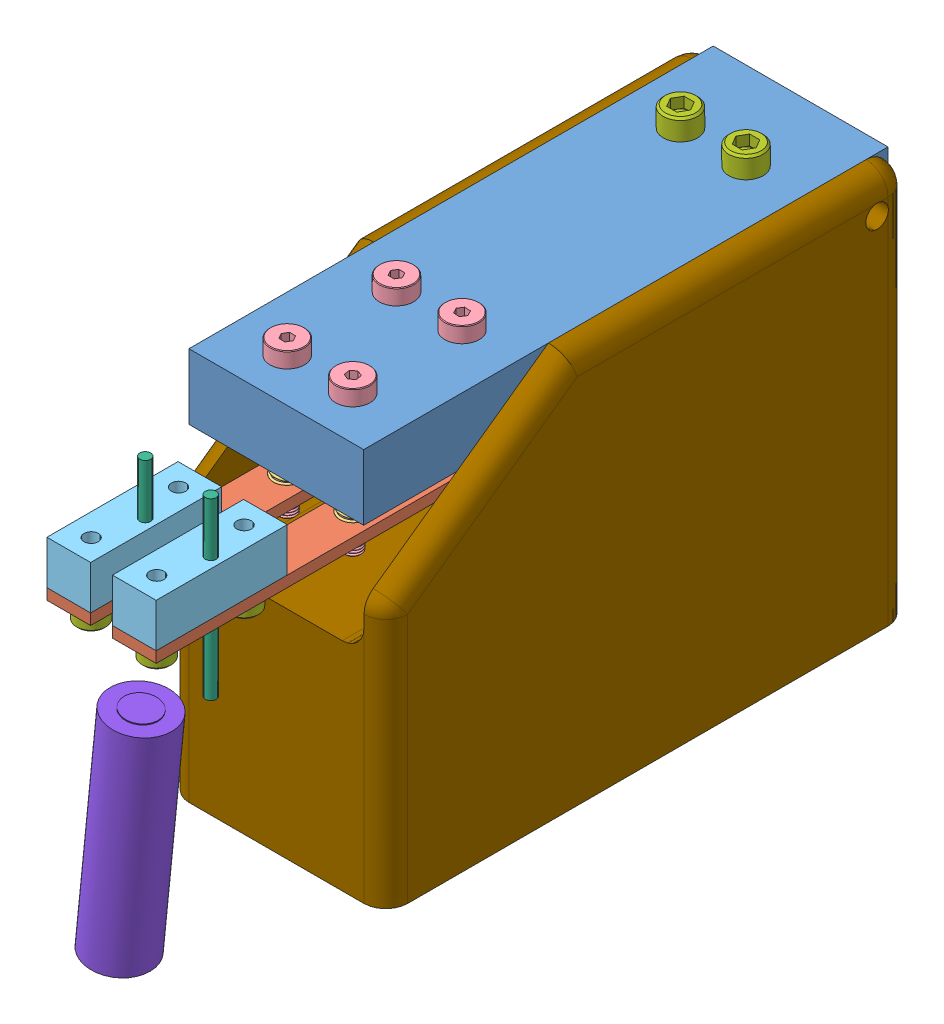
SolidWorks assembly WelderArmAssy, configuration Default. Lengths in mm.
Overall size (63.5 125.04 207.43).
23 component instances, 9 part files, 40 mates.
Components (placement in the parent):
- WelderArm-1: WelderArm [Default] at origin size (50.8 19.05 152.4)
- copperBusBar-1: copperBusBar [Default] at (28.575 -14.125 0) size (12.7 3.17 203.2)
- copperBusBar-2: copperBusBar [Default] at (9.525 -14.125 0) size (12.7 3.17 203.2)
- 9657K303_STEEL COMPRESSION SPRING-1: 9657K303_STEEL COMPRESSION SPRING [9657K303] at (34.8782 -10.95 139.5847) x (1 0 0) z (0 -1 0) size (8.16 8.28 25.73)
- socket head shoulder screw2_am-1: socket head shoulder screw2_am [B18.3.3M - 6.5 x 30 SHSS --S] at (34.925 23.55 139.7) x (0 -1 0) z (0.988219 0 -0.153046) size (44.25 10 10)
- socket head shoulder screw2_am-2: socket head shoulder screw2_am [B18.3.3M - 6.5 x 30 SHSS --S] at (15.875 23.55 139.7) x (0 -1 0) z (-0.008465 0 0.999964) size (44.25 10 10)
- 9657K303_STEEL COMPRESSION SPRING-2: 9657K303_STEEL COMPRESSION SPRING [9657K303] at (15.8175 -10.95 139.7949) x (1 0 0) z (0 -1 0) size (8.16 8.28 25.73)
- socket head shoulder screw2_am-3: socket head shoulder screw2_am [B18.3.3M - 6.5 x 30 SHSS --S] at (15.875 23.55 107.95) x (0 -1 0) z (-0.008465 0 0.999964) size (44.25 10 10)
- socket head shoulder screw2_am-5: socket head shoulder screw2_am [B18.3.3M - 6.5 x 30 SHSS --S] at (34.925 23.55 107.95) x (0 -1 0) z (0.839971 0 0.542632) size (44.25 10 10)
- Mini_Bus_Block-3: Mini_Bus_Block [Default] at (41.275 -10.95 203.2) x (-1 0 0) z (0 0 -1) size (12.7 12.7 38.1)
- Mini_Bus_Block-4: Mini_Bus_Block [Default] at (22.225 -10.95 203.2) x (-1 0 0) z (0 0 -1) size (12.7 12.7 38.1)
- CopperElectrode-1: CopperElectrode [Default] at (38.1 -33.4948 184.15) x (0.72725 0 -0.686373) z (0.686373 0 0.72725) size (3.17 50.8 3.17)
- CopperElectrode-2: CopperElectrode [Default] at (19.05 -33.3788 184.15) x (-0.864045 0 0.503415) z (-0.503415 0 -0.864045) size (3.17 50.8 3.17)
- socket head cap screw_am-1: socket head cap screw_am [B18.3.1M - 5 x 0.8 x 10 Hex SHCS -- 10NHX] at (16.0317 -19.125 196.85) x (0 1 0) z (0 0 1) size (15 8.5 8.5)
- socket head cap screw_am-2: socket head cap screw_am [B18.3.1M - 5 x 0.8 x 10 Hex SHCS -- 10NHX] at (16.0317 -19.125 171.45) x (0 1 0) z (0.419205 0 0.907892) size (15 8.5 8.5)
- socket head cap screw_am-3: socket head cap screw_am [B18.3.1M - 5 x 0.8 x 10 Hex SHCS -- 10NHX] at (35.0817 -19.125 196.85) x (0 1 0) z (0 0 1) size (15 8.5 8.5)
- socket head cap screw_am-4: socket head cap screw_am [B18.3.1M - 5 x 0.8 x 10 Hex SHCS -- 10NHX] at (35.0817 -19.125 171.45) x (0 1 0) z (0 0 1) size (15 8.5 8.5)
- socket head cap screw_am-5: socket head cap screw_am [B18.3.1M - 6 x 1.0 x 40 Hex SHCS -- 24NHX] at (15.875 25.05 25.4) x (0 -1 0) z (0 0 1) size (46 10 10)
- socket head cap screw_am-7: socket head cap screw_am [B18.3.1M - 6 x 1.0 x 40 Hex SHCS -- 24NHX] at (34.925 25.05 25.4) x (0 -1 0) z (0 0 1) size (46 10 10)
- 9657K303_STEEL COMPRESSION SPRING-7: 9657K303_STEEL COMPRESSION SPRING [9657K303] at (34.5426 -10.95 108.0658) x (1 0 0) z (0 -1 0) size (8.16 8.28 25.73)
- 9657K303_STEEL COMPRESSION SPRING-8: 9657K303_STEEL COMPRESSION SPRING [9657K303] at (16.1134 -10.95 107.8329) x (1 0 0) z (0 -1 0) size (8.16 8.28 25.73)
- 18650-1: 18650 [Default] at (23.2712 -98.7389 195.9651) x (0.198702 -0.032867 0.979509) z (-0.973928 0.105003 0.201093) size (18.2 65 18.2)
- stand-1: stand [Default] at (57.15 -95.25 0) x (-1 0 0) z (0 0 -1) size (63.5 114.3 152.32)
Mates (geometry in assembly coordinates):
- Coincident1: coincident aligned: plane of WelderArm-1 through (0 0 0) normal (0 0 -1); plane of copperBusBar-2 through (9.525 -14.125 0) normal (0 0 -1)
- Coincident2: coincident aligned: plane of WelderArm-1 through (0 0 0) normal (0 0 -1); plane of copperBusBar-1 through (28.575 -14.125 0) normal (0 0 -1)
- Coincident4: coincident aligned: plane of copperBusBar-1 through (28.575 -10.95 203.2) normal (0 1 0); plane of copperBusBar-2 through (9.525 -10.95 203.2) normal (0 1 0)
- Distance3: distance = 9.525 mm aligned: plane of copperBusBar-1 through (41.275 -14.125 203.2) normal (1 0 0); plane of WelderArm-1 through (50.8 0 152.4) normal (1 0 0)
- Concentric1: concentric anti-aligned: cylinder of copperBusBar-1 through (34.925 -14.125 139.7) axis (0 -1 0) radius 2.1; cylinder of socket head shoulder screw2_am-1 through (34.925 29.9 139.7) axis (0 1 0) radius 3.2435
- Coincident7: coincident anti-aligned: plane of copperBusBar-1 through (28.575 -10.95 203.2) normal (0 1 0); plane of socket head shoulder screw2_am-1 through (34.4286 -10.95 136.4947) normal (0 -1 0)
- Coincident8: coincident anti-aligned: plane of copperBusBar-1 through (28.575 -10.95 203.2) normal (0 1 0); plane of 9657K303_STEEL COMPRESSION SPRING-1 through (34.8782 -10.95 139.5847) normal (0 -1 0)
- Concentric3: concentric anti-aligned: cylinder of copperBusBar-2 through (15.875 -14.125 139.7) axis (0 -1 0) radius 2.1; cylinder of socket head shoulder screw2_am-2 through (15.875 29.9 139.7) axis (0 1 0) radius 3.2435
- Coincident9: coincident anti-aligned: plane of copperBusBar-2 through (9.525 -10.95 203.2) normal (0 1 0); plane of socket head shoulder screw2_am-2 through (19.1184 -10.95 139.7275) normal (0 -1 0)
- Coincident10: coincident anti-aligned: plane of copperBusBar-2 through (9.525 -10.95 203.2) normal (0 1 0); plane of 9657K303_STEEL COMPRESSION SPRING-2 through (15.8175 -10.95 139.7949) normal (0 -1 0)
- Concentric4: concentric anti-aligned: cylinder of copperBusBar-2 through (15.875 -14.125 107.95) axis (0 -1 0) radius 2.1; cylinder of socket head shoulder screw2_am-3 through (15.875 29.9 107.95) axis (0 1 0) radius 3.2435
- Coincident11: coincident anti-aligned: plane of copperBusBar-2 through (9.525 -10.95 203.2) normal (0 1 0); plane of socket head shoulder screw2_am-3 through (19.1184 -10.95 107.9775) normal (0 -1 0)
- Concentric6: concentric anti-aligned: cylinder of copperBusBar-1 through (34.925 -14.125 107.95) axis (0 -1 0) radius 2.1; cylinder of socket head shoulder screw2_am-5 through (34.925 29.9 107.95) axis (0 1 0) radius 3.2435
- Coincident12: coincident anti-aligned: plane of copperBusBar-1 through (28.575 -10.95 203.2) normal (0 1 0); plane of socket head shoulder screw2_am-5 through (36.685 -10.95 105.2256) normal (0 -1 0)
- Coincident19: coincident aligned: plane of copperBusBar-1 through (28.575 -14.125 203.2) normal (0 0 1); plane of Mini_Bus_Block-3 through (41.275 -10.95 203.2) normal (0 0 1)
- Coincident20: coincident anti-aligned: plane of copperBusBar-1 through (28.575 -10.95 203.2) normal (0 1 0); plane of Mini_Bus_Block-3 through (41.275 -10.95 165.1) normal (0 -1 0)
- Coincident23: coincident aligned: plane of copperBusBar-2 through (9.525 -14.125 203.2) normal (0 0 1); plane of Mini_Bus_Block-4 through (22.225 -10.95 203.2) normal (0 0 1)
- Coincident24: coincident anti-aligned: plane of copperBusBar-2 through (9.525 -10.95 203.2) normal (0 1 0); plane of Mini_Bus_Block-4 through (22.225 -10.95 165.1) normal (0 -1 0)
- Coincident25: coincident aligned: plane of copperBusBar-2 through (22.225 -14.125 203.2) normal (1 0 0); plane of Mini_Bus_Block-4 through (22.225 -10.95 165.1) normal (1 0 0)
- Concentric7: concentric anti-aligned: cylinder of Mini_Bus_Block-3 through (38.1 1.75 184.15) axis (0 1 0) radius 1.5875; cylinder of CopperElectrode-1 through (38.1 17.3052 184.15) axis (0 -1 0) radius 1.5875
- Concentric8: concentric anti-aligned: cylinder of Mini_Bus_Block-4 through (19.05 1.75 184.15) axis (0 1 0) radius 1.5875; cylinder of CopperElectrode-2 through (19.05 17.4212 184.15) axis (0 -1 0) radius 1.5875
- Concentric9: concentric anti-aligned: cylinder of Mini_Bus_Block-4 through (16.0317 1.75 171.45) axis (0 1 0) radius 2.1; cylinder of socket head cap screw_am-2 through (16.0317 -50.875 171.45) axis (0 -1 0) radius 2.5
- Coincident26: coincident anti-aligned: plane of copperBusBar-2 through (9.525 -14.125 203.2) normal (0 -1 0); plane of socket head cap screw_am-2 through (12.1732 -14.125 173.2316) normal (0 1 0)
- Concentric10: concentric anti-aligned: cylinder of Mini_Bus_Block-4 through (16.0317 1.75 196.85) axis (0 1 0) radius 2.1; cylinder of socket head cap screw_am-1 through (16.0317 -50.875 196.85) axis (0 -1 0) radius 2.5
- Coincident27: coincident anti-aligned: plane of copperBusBar-2 through (9.525 -14.125 203.2) normal (0 -1 0); plane of socket head cap screw_am-1 through (11.7817 -14.125 196.85) normal (0 1 0)
- Concentric11: concentric anti-aligned: cylinder of Mini_Bus_Block-3 through (35.0817 1.75 196.85) axis (0 1 0) radius 2.1; cylinder of socket head cap screw_am-3 through (35.0817 -50.875 196.85) axis (0 -1 0) radius 2.5
- Coincident28: coincident anti-aligned: plane of copperBusBar-1 through (28.575 -14.125 203.2) normal (0 -1 0); plane of socket head cap screw_am-3 through (30.8317 -14.125 196.85) normal (0 1 0)
- Concentric12: concentric anti-aligned: cylinder of Mini_Bus_Block-3 through (35.0817 1.75 171.45) axis (0 1 0) radius 2.1; cylinder of socket head cap screw_am-4 through (35.0817 -50.875 171.45) axis (0 -1 0) radius 2.5
- Coincident29: coincident anti-aligned: plane of copperBusBar-1 through (28.575 -14.125 203.2) normal (0 -1 0); plane of socket head cap screw_am-4 through (30.8317 -14.125 171.45) normal (0 1 0)
- Concentric13: concentric anti-aligned: cylinder of WelderArm-1 through (15.875 0 25.4) axis (0 -1 0) radius 3.3; cylinder of socket head cap screw_am-5 through (15.875 56.8 25.4) axis (0 1 0) radius 3
- Coincident30: coincident anti-aligned: plane of WelderArm-1 through (0 19.05 152.4) normal (0 1 0); plane of socket head cap screw_am-5 through (20.875 19.05 25.4) normal (0 -1 0)
- Concentric14: concentric anti-aligned: cylinder of WelderArm-1 through (34.925 0 25.4) axis (0 -1 0) radius 3.3; cylinder of socket head cap screw_am-7 through (34.925 56.8 25.4) axis (0 1 0) radius 3
- Coincident31: coincident anti-aligned: plane of WelderArm-1 through (0 19.05 152.4) normal (0 1 0); plane of socket head cap screw_am-7 through (39.925 19.05 25.4) normal (0 -1 0)
- Coincident32: coincident anti-aligned: plane of copperBusBar-2 through (9.525 -10.95 203.2) normal (0 1 0); plane of 9657K303_STEEL COMPRESSION SPRING-7 through (34.5426 -10.95 108.0658) normal (0 -1 0)
- Coincident33: coincident anti-aligned: plane of copperBusBar-1 through (28.575 -10.95 203.2) normal (0 1 0); plane of 9657K303_STEEL COMPRESSION SPRING-8 through (16.1134 -10.95 107.8329) normal (0 -1 0)
- Concentric15: concentric anti-aligned: cylinder of WelderArm-1 through (15.875 0 107.95) axis (0 -1 0) radius 3.3; cylinder of socket head shoulder screw2_am-3 through (15.875 29.9 107.95) axis (0 1 0) radius 3.2435
- Coincident34: coincident anti-aligned: plane of WelderArm-1 through (0 19.05 152.4) normal (0 1 0); plane of socket head shoulder screw2_am-3 through (20.8748 19.05 107.9923) normal (0 -1 0)
- Coincident35: coincident anti-aligned: plane of WelderArm-1 through (0 0 152.4) normal (-1 0 0); plane of stand-1 through (0 -32.2663 152.3225) normal (1 0 0)
- Coincident37: coincident anti-aligned: line of WelderArm-1 through (0 19.05 0) axis (0 -1 0); line of stand-1 through (0 -25.9163 0) axis (0 1 0)
- Coincident38: coincident aligned: line of WelderArm-1 through (0 19.05 152.4) axis (0 0 -1); line of stand-1 through (0 19.05 98.7056) axis (0 0 -1)
